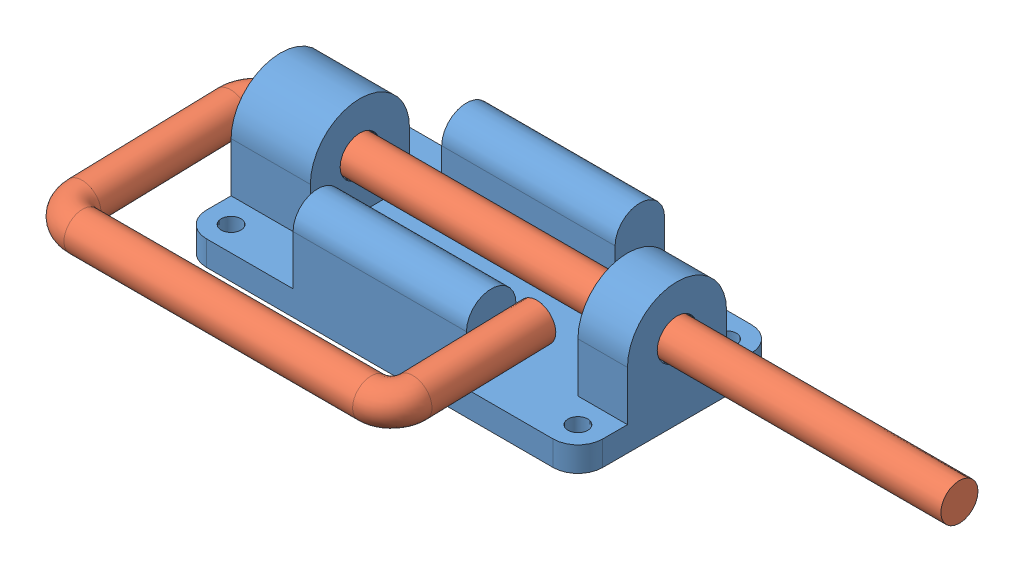
SolidWorks assembly Assem1, configuration Varsayılan. Lengths in mm.
Overall size (145.75 25 63.84).
2 component instances, 2 part files, 2 mates.
Components (placement in the parent):
- Part1-1: Part1 [Varsayılan] at (4.3105 -10.5603 80) size (80 25 40)
- Part2-1: Part2 [Varsayılan] at (101.3105 4.4397 80) x (1 0 0) z (0 0.999622 0.027482) size (145.75 47.5 7.5)
Mates (geometry in assembly coordinates):
- Concentric1: concentric anti-aligned: cylinder of Part1-1 through (28.3105 4.4397 80) axis (1 0 0) radius 4; cylinder of Part2-1 through (101.3105 4.4397 80) axis (-1 0 0) radius 3.75
- Distance1: distance = 5 mm: plane of Part1-1 through (-35.6895 -5.5603 65) normal (-1 0 0); cylinder of Part2-1 through (-40.6895 4.3023 84.9981) axis (0 -0.027482 0.999622) radius 3.75
